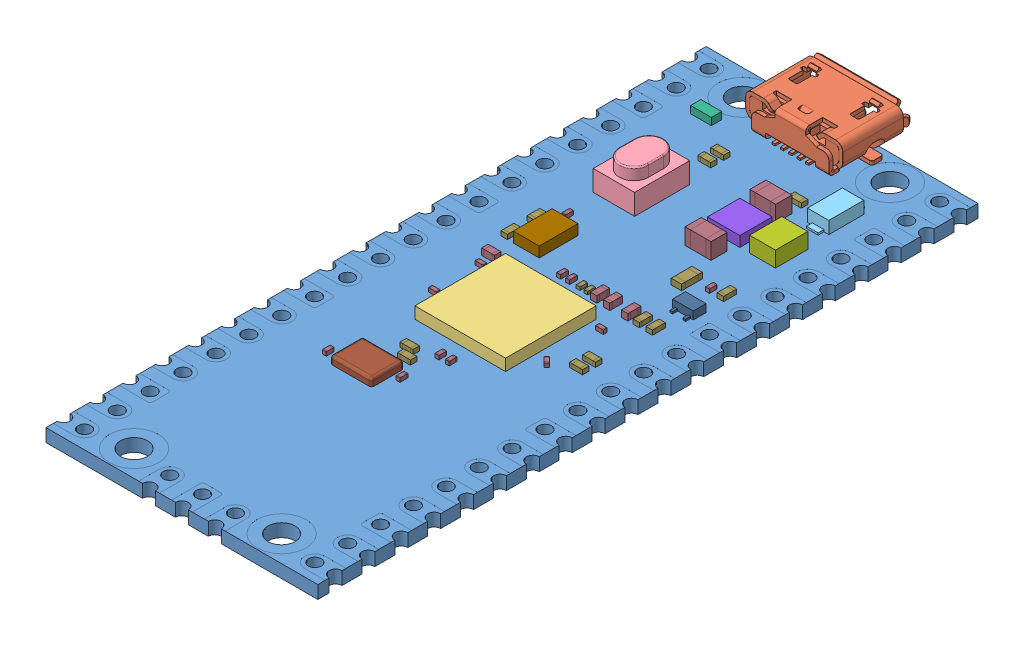
SolidWorks assembly Raspberry Pi Pico-R3, configuration Default. Lengths in mm.
Overall size (21 3.69 52.43).
44 component instances, 13 part files, 131 mates.
Components (placement in the parent):
- PCB, Raspberry Pi Pico-R3-1: PCB, Raspberry Pi Pico-R3 [Default] at origin size (21 1 51)
- MicroUSB Port, Raspberry Pi Pico-R3-1: MicroUSB Port, Raspberry Pi Pico-R3 [Default] at (0 0.5 -24.35) x (-1 0 0) z (0 0 -1) size (7.97 2.92 5.43)
- RP2040 Microcontroller, Raspberry Pi Pico-R3-1: RP2040 Microcontroller, Raspberry Pi Pico-R3 [Default] at (0 0.5 0.5) size (7 0.9 7)
- SW1, Tact Switch, Raspberry Pi Pico-R3-1: SW1, Tact Switch, Raspberry Pi Pico-R3 [Default] at (-3.5 0.5 -13.5) size (3.2 2.5 4.25)
- D1, Diode, Schottky, Raspberry Pi Pico-R3-1: D1, Diode, Schottky, Raspberry Pi Pico-R3 [Default] at (6 0.5 -19) size (1.65 0.95 3.6)
- D2, QSME-C194, LED, Raspberry Pi Pico-R3-1: D2, QSME-C194, LED, Raspberry Pi Pico-R3 [Default] at (-5.8 0.5 -20.8) size (1.6 0.55 0.8)
- L1, Inductor, Raspberry Pi Pico-R3-1: L1, Inductor, Raspberry Pi Pico-R3 [Default] at (6 0.5 -14.6) size (2 1.2 2.5)
- U2, RT6150B-33GQW, Buck Boost Converter, Raspberry Pi Pico-R3-1: U2, RT6150B-33GQW, Buck Boost Converter, Raspberry Pi Pico-R3 [Default] at (3 0.5 -14.6) size (2.5 0.8 2.5)
- U3, W25Q16JVUXIQ, Serial NOR Flash 16 Mbit, Raspberry Pi Pico-R3-1: U3, W25Q16JVUXIQ, Serial NOR Flash 16 Mbit, Raspberry Pi Pico-R3 [Default] at (-3.8 0.5 -6.4) size (2 0.8 3)
- Q1, MOSFET, DMG1012T, Raspberry Pi Pico-R3-1: Q1, MOSFET, DMG1012T, Raspberry Pi Pico-R3 [Default] at (6.5 0.5 -7.2) size (1.6 0.6 1.8)
- X1, X12M000000S096, 12 Mhz Crystal Resonator, Raspberry Pi Pico-R3-1: X1, X12M000000S096, 12 Mhz Crystal Resonator, Raspberry Pi Pico-R3 [Default] at (-2.2 0.5 9) size (3.2 0.6 2.5)
- SMD Resistor, Configurable, Raspberry Pi Pico-R3-1: SMD Resistor, Configurable, Raspberry Pi Pico-R3 [R1] at (6.2 0.5 1) x (0 0 -1) z (1 0 0) size (0.5 0.35 1)
- SMD Resistor, Configurable, Raspberry Pi Pico-R3-2: SMD Resistor, Configurable, Raspberry Pi Pico-R3 [R2] at (3.5 0.5 -18.6) x (0 0 -1) z (1 0 0) size (0.5 0.35 1)
- SMD Resistor, Configurable, Raspberry Pi Pico-R3-3: SMD Resistor, Configurable, Raspberry Pi Pico-R3 [R3] at (-2.7 0.5 -17.8) x (0 0 -1) z (1 0 0) size (0.5 0.35 1)
- SMD Resistor, Configurable, Raspberry Pi Pico-R3-4: SMD Resistor, Configurable, Raspberry Pi Pico-R3 [R4] at (-5.5 0.5 -5.4) x (-1 0 0) z (0 0 -1) size (0.5 0.35 1)
- SMD Resistor, Configurable, Raspberry Pi Pico-R3-5: SMD Resistor, Configurable, Raspberry Pi Pico-R3 [R5] at (7 0.5 -9.6) x (-1 0 0) z (0 0 -1) size (0.5 0.35 1)
- SMD Resistor, Configurable, Raspberry Pi Pico-R3-6: SMD Resistor, Configurable, Raspberry Pi Pico-R3 [R6] at (6.5 0.5 -4.6) x (-1 0 0) z (0 0 -1) size (0.5 0.35 1)
- SMD Resistor, Configurable, Raspberry Pi Pico-R3-7: SMD Resistor, Configurable, Raspberry Pi Pico-R3 [R7] at (4.5 0.5 -9) x (-1 0 0) z (0 0 -1) size (0.8 0.45 1.6)
- SMD Resistor, Configurable, Raspberry Pi Pico-R3-8: SMD Resistor, Configurable, Raspberry Pi Pico-R3 [R8] at (-2.7 0.5 -18.8) x (0 0 -1) z (1 0 0) size (0.5 0.35 1)
- SMD Resistor, Configurable, Raspberry Pi Pico-R3-9: SMD Resistor, Configurable, Raspberry Pi Pico-R3 [R9] at (5.5 0.5 -4.6) x (-1 0 0) z (0 0 -1) size (0.5 0.35 1)
- SMD Resistor, Configurable, Raspberry Pi Pico-R3-10: SMD Resistor, Configurable, Raspberry Pi Pico-R3 [R10] at (6.2 0.5 0) x (0 0 -1) z (1 0 0) size (0.5 0.35 1)
- SMD Resistor, Configurable, Raspberry Pi Pico-R3-11: SMD Resistor, Configurable, Raspberry Pi Pico-R3 [R11] at (-5.5 0.5 -7.4) size (0.5 0.35 1)
- SMD Resistor, Configurable, Raspberry Pi Pico-R3-12: SMD Resistor, Configurable, Raspberry Pi Pico-R3 [R12] at (0.8 0.5 -4.6) x (-1 0 0) z (0 0 -1) size (0.3 0.23 0.6)
- SMD Resistor, Configurable, Raspberry Pi Pico-R3-13: SMD Resistor, Configurable, Raspberry Pi Pico-R3 [R13] at (1.4 0.5 -4.6) x (-1 0 0) z (0 0 -1) size (0.3 0.23 0.6)
- SMD Resistor, Configurable, Raspberry Pi Pico-R3-14: SMD Resistor, Configurable, Raspberry Pi Pico-R3 [R14] at (-1.1 0.5 7) x (0 0 -1) z (1 0 0) size (0.5 0.35 1)
- SMD Resistor, Configurable, Raspberry Pi Pico-R3-15: SMD Resistor, Configurable, Raspberry Pi Pico-R3 [R15] at (-1.7 0.5 6.2) x (0 0 -1) z (1 0 0) size (0.5 0.35 1)
- SMD Capacitor, Configurable, Raspberry Pi Pico-R3-1: SMD Capacitor, Configurable, Raspberry Pi Pico-R3 [C1] at (3 0.5 -17) x (0 0 -1) z (1 0 0) size (1.25 1.25 2)
- SMD Capacitor, Configurable, Raspberry Pi Pico-R3-2: SMD Capacitor, Configurable, Raspberry Pi Pico-R3 [C2] at (3 0.5 -12) x (0 0 -1) z (1 0 0) size (1.25 1.25 2)
- SMD Capacitor, Configurable, Raspberry Pi Pico-R3-3: SMD Capacitor, Configurable, Raspberry Pi Pico-R3 [C3] at (6 0.5 -9.4) size (0.3 0.3 0.6)
- SMD Capacitor, Configurable, Raspberry Pi Pico-R3-4: SMD Capacitor, Configurable, Raspberry Pi Pico-R3 [C4] at (-4.5 0.5 -2.1) x (0 0 1) z (-1 0 0) size (0.3 0.3 0.6)
- SMD Capacitor, Configurable, Raspberry Pi Pico-R3-5: SMD Capacitor, Configurable, Raspberry Pi Pico-R3 [C5] at (-4.5 0.5 1.5) x (0 0 1) z (-1 0 0) size (0.3 0.3 0.6)
- SMD Capacitor, Configurable, Raspberry Pi Pico-R3-6: SMD Capacitor, Configurable, Raspberry Pi Pico-R3 [C6] at (4.6 0.5 1.9) x (0.707107 0 -0.707107) z (0.707107 0 0.707107) size (0.3 0.3 0.6)
- SMD Capacitor, Configurable, Raspberry Pi Pico-R3-7: SMD Capacitor, Configurable, Raspberry Pi Pico-R3 [C7] at (4.5 0.5 -2.4) x (0 0 1) z (-1 0 0) size (0.3 0.3 0.6)
- SMD Capacitor, Configurable, Raspberry Pi Pico-R3-8: SMD Capacitor, Configurable, Raspberry Pi Pico-R3 [C8] at (0 0.5 5.5) size (0.3 0.3 0.6)
- SMD Capacitor, Configurable, Raspberry Pi Pico-R3-9: SMD Capacitor, Configurable, Raspberry Pi Pico-R3 [C9] at (0.8 0.5 5.5) size (0.3 0.3 0.6)
- SMD Capacitor, Configurable, Raspberry Pi Pico-R3-10: SMD Capacitor, Configurable, Raspberry Pi Pico-R3 [C10] at (0 0.5 -4.6) size (0.3 0.3 0.6)
- SMD Capacitor, Configurable, Raspberry Pi Pico-R3-11: SMD Capacitor, Configurable, Raspberry Pi Pico-R3 [C11] at (-0.7 0.5 -4.6) size (0.3 0.3 0.6)
- SMD Capacitor, Configurable, Raspberry Pi Pico-R3-19: SMD Capacitor, Configurable, Raspberry Pi Pico-R3 [C12] at (2.2 0.5 -4.6) size (0.5 0.5 1)
- SMD Capacitor, Configurable, Raspberry Pi Pico-R3-20: SMD Capacitor, Configurable, Raspberry Pi Pico-R3 [C13] at (4.6 0.5 -4.6) size (0.5 0.5 1)
- SMD Capacitor, Configurable, Raspberry Pi Pico-R3-21: SMD Capacitor, Configurable, Raspberry Pi Pico-R3 [C14] at (3.2 0.5 -4.6) size (0.5 0.5 1)
- SMD Capacitor, Configurable, Raspberry Pi Pico-R3-22: SMD Capacitor, Configurable, Raspberry Pi Pico-R3 [C15] at (-4.5 0.5 -8.8) size (0.3 0.3 0.6)
- SMD Capacitor, Configurable, Raspberry Pi Pico-R3-23: SMD Capacitor, Configurable, Raspberry Pi Pico-R3 [C16] at (-4.6 0.5 9.6) size (0.3 0.3 0.6)
- SMD Capacitor, Configurable, Raspberry Pi Pico-R3-24: SMD Capacitor, Configurable, Raspberry Pi Pico-R3 [C17] at (0 0.5 8.5) size (0.3 0.3 0.6)
- SMD Capacitor, Configurable, Raspberry Pi Pico-R3-18: SMD Capacitor, Configurable, Raspberry Pi Pico-R3 [C18] at (-4.7 0.5 -3.1) x (0 0 1) z (-1 0 0) size (0.5 0.5 1)
Mates (geometry in assembly coordinates):
- Coincident1: coordinate: point of assembly; point of PCB, Raspberry Pi Pico-R3-1; point of assembly
- Coincident2: coincident: plane of assembly through (0 0 0) normal (1 0 0); plane of MicroUSB Port, Raspberry Pi Pico-R3-1 through (0 0.5 -24.35) normal (-1 0 0); plane of assembly
- Coincident4: coincident: plane of assembly; plane of assembly; plane of PCB, Raspberry Pi Pico-R3-1 through (0 0.5 0) normal (0 1 0); plane of MicroUSB Port, Raspberry Pi Pico-R3-1 through (0 0.5 -24.35) normal (0 1 0)
- Distance1: distance: plane of assembly; plane of assembly; plane of PCB, Raspberry Pi Pico-R3-1 through (-10.5 -0.5 -25.5) normal (0 0 -1); plane of MicroUSB Port, Raspberry Pi Pico-R3-1 through (-1.2 2.0268 -21.5) normal (0 0 1)
- Coincident5: coincident: plane of assembly; plane of assembly; plane of PCB, Raspberry Pi Pico-R3-1 through (0 0.5 0) normal (0 1 0); plane of RP2040 Microcontroller, Raspberry Pi Pico-R3-1 through (0 0.5 0.5) normal (0 -1 0)
- Coincident6: coincident: plane of assembly through (0 0 0) normal (1 0 0); plane of RP2040 Microcontroller, Raspberry Pi Pico-R3-1 through (0 0.5 0.5) normal (1 0 0); plane of assembly
- Coincident7: coincident: plane of assembly; plane of assembly; plane of PCB, Raspberry Pi Pico-R3-1 through (0 0.5 0) normal (0 1 0); plane of SW1, Tact Switch, Raspberry Pi Pico-R3-1 through (-3.5 0.5 -13.5) normal (0 -1 0)
- Distance2: distance = 3.5 mm: plane of assembly through (0 0 0) normal (1 0 0); plane of SW1, Tact Switch, Raspberry Pi Pico-R3-1 through (-3.5 0.5 -13.5) normal (1 0 0); plane of assembly
- Distance3: distance = 13.5 mm: plane of assembly through (0 0 0) normal (0 0 1); plane of assembly; plane of SW1, Tact Switch, Raspberry Pi Pico-R3-1 through (-3.5 0.5 -13.5) normal (0 0 1)
- Coincident8: coincident: plane of assembly; plane of assembly; plane of PCB, Raspberry Pi Pico-R3-1 through (0 0.5 0) normal (0 1 0); plane of D1, Diode, Schottky, Raspberry Pi Pico-R3-1 through (6 0.5 -19) normal (0 -1 0)
- Distance4: distance = 6 mm: plane of assembly through (0 0 0) normal (1 0 0); plane of D1, Diode, Schottky, Raspberry Pi Pico-R3-1 through (6 0.5 -19) normal (1 0 0); plane of assembly
- Distance5: distance = 19 mm: plane of assembly through (0 0 0) normal (0 0 1); plane of assembly; plane of D1, Diode, Schottky, Raspberry Pi Pico-R3-1 through (6 0.5 -19) normal (0 0 1)
- Coincident9: coincident: plane of assembly; plane of assembly; plane of PCB, Raspberry Pi Pico-R3-1 through (0 0.5 0) normal (0 1 0); plane of L1, Inductor, Raspberry Pi Pico-R3-1 through (6 0.5 -14.6) normal (0 -1 0)
- Coincident10: coincident: plane of assembly; plane of assembly; plane of D1, Diode, Schottky, Raspberry Pi Pico-R3-1 through (6 0.5 -19) normal (1 0 0); plane of L1, Inductor, Raspberry Pi Pico-R3-1 through (6 0.5 -14.6) normal (1 0 0)
- Distance6: distance = 4.4 mm: plane of assembly; plane of assembly; plane of L1, Inductor, Raspberry Pi Pico-R3-1 through (6 0.5 -14.6) normal (0 0 1); plane of D1, Diode, Schottky, Raspberry Pi Pico-R3-1 through (6 0.5 -19) normal (0 0 1)
- Coincident11: coincident: plane of assembly; plane of assembly; plane of PCB, Raspberry Pi Pico-R3-1 through (0 0.5 0) normal (0 1 0); plane of SMD Resistor, Configurable, Raspberry Pi Pico-R3-1 through (6.2 0.5 1) normal (0 -1 0)
- Distance8: distance = 6.2 mm: plane of assembly through (0 0 0) normal (1 0 0); plane of SMD Resistor, Configurable, Raspberry Pi Pico-R3-1 through (6.2 0.5 1) normal (1 0 0); plane of assembly
- Distance9: distance = 1 mm: plane of assembly through (0 0 0) normal (0 0 1); plane of SMD Resistor, Configurable, Raspberry Pi Pico-R3-1 through (6.2 0.5 1) normal (0 0 -1); plane of assembly
- Coincident13: coincident: plane of assembly; plane of assembly; plane of PCB, Raspberry Pi Pico-R3-1 through (0 0.5 0) normal (0 1 0); plane of SMD Resistor, Configurable, Raspberry Pi Pico-R3-2 through (3.5 0.5 -18.6) normal (0 -1 0)
- Distance10: distance = 3.5 mm: plane of assembly through (0 0 0) normal (1 0 0); plane of SMD Resistor, Configurable, Raspberry Pi Pico-R3-2 through (3.5 0.5 -18.6) normal (1 0 0); plane of assembly
- Distance11: distance = 18.6 mm: plane of assembly through (0 0 0) normal (0 0 1); plane of SMD Resistor, Configurable, Raspberry Pi Pico-R3-2 through (3.5 0.5 -18.6) normal (0 0 -1); plane of assembly
- Coincident14: coincident: plane of assembly; plane of assembly; plane of PCB, Raspberry Pi Pico-R3-1 through (0 0.5 0) normal (0 1 0); plane of SMD Resistor, Configurable, Raspberry Pi Pico-R3-3 through (-2.7 0.5 -17.8) normal (0 -1 0)
- Coincident15: coincident: plane of assembly; plane of assembly; plane of PCB, Raspberry Pi Pico-R3-1 through (0 0.5 0) normal (0 1 0); plane of SMD Resistor, Configurable, Raspberry Pi Pico-R3-4 through (-5.5 0.5 -5.4) normal (0 -1 0)
- Coincident16: coincident: plane of assembly; plane of assembly; plane of PCB, Raspberry Pi Pico-R3-1 through (0 0.5 0) normal (0 1 0); plane of SMD Resistor, Configurable, Raspberry Pi Pico-R3-5 through (7 0.5 -9.6) normal (0 -1 0)
- Coincident17: coincident: plane of assembly; plane of assembly; plane of PCB, Raspberry Pi Pico-R3-1 through (0 0.5 0) normal (0 1 0); plane of SMD Resistor, Configurable, Raspberry Pi Pico-R3-6 through (6.5 0.5 -4.6) normal (0 -1 0)
- Coincident18: coincident: plane of assembly; plane of assembly; plane of PCB, Raspberry Pi Pico-R3-1 through (0 0.5 0) normal (0 1 0); plane of SMD Resistor, Configurable, Raspberry Pi Pico-R3-7 through (4.5 0.5 -9) normal (0 -1 0)
- Coincident19: coincident: plane of assembly; plane of assembly; plane of PCB, Raspberry Pi Pico-R3-1 through (0 0.5 0) normal (0 1 0); plane of SMD Resistor, Configurable, Raspberry Pi Pico-R3-8 through (-2.7 0.5 -18.8) normal (0 -1 0)
- Coincident20: coincident: plane of assembly; plane of assembly; plane of PCB, Raspberry Pi Pico-R3-1 through (0 0.5 0) normal (0 1 0); plane of SMD Resistor, Configurable, Raspberry Pi Pico-R3-9 through (5.5 0.5 -4.6) normal (0 -1 0)
- Coincident21: coincident: plane of assembly; plane of assembly; plane of PCB, Raspberry Pi Pico-R3-1 through (0 0.5 0) normal (0 1 0); plane of SMD Resistor, Configurable, Raspberry Pi Pico-R3-10 through (6.2 0.5 0) normal (0 -1 0)
- Coincident22: coincident: plane of assembly; plane of assembly; plane of PCB, Raspberry Pi Pico-R3-1 through (0 0.5 0) normal (0 1 0); plane of SMD Resistor, Configurable, Raspberry Pi Pico-R3-11 through (-5.5 0.5 -7.4) normal (0 -1 0)
- Coincident23: coincident: plane of assembly; plane of assembly; plane of PCB, Raspberry Pi Pico-R3-1 through (0 0.5 0) normal (0 1 0); plane of SMD Resistor, Configurable, Raspberry Pi Pico-R3-12 through (0.8 0.5 -4.6) normal (0 -1 0)
- Coincident24: coincident: plane of assembly; plane of assembly; plane of PCB, Raspberry Pi Pico-R3-1 through (0 0.5 0) normal (0 1 0); plane of SMD Resistor, Configurable, Raspberry Pi Pico-R3-13 through (1.4 0.5 -4.6) normal (0 -1 0)
- Coincident25: coincident: plane of assembly; plane of assembly; plane of PCB, Raspberry Pi Pico-R3-1 through (0 0.5 0) normal (0 1 0); plane of SMD Resistor, Configurable, Raspberry Pi Pico-R3-14 through (-1.1 0.5 7) normal (0 -1 0)
- Coincident26: coincident: plane of assembly; plane of assembly; plane of PCB, Raspberry Pi Pico-R3-1 through (0 0.5 0) normal (0 1 0); plane of SMD Resistor, Configurable, Raspberry Pi Pico-R3-15 through (-1.7 0.5 6.2) normal (0 -1 0)
- Distance12: distance = 2.7 mm: plane of assembly through (0 0 0) normal (1 0 0); plane of SMD Resistor, Configurable, Raspberry Pi Pico-R3-3 through (-2.7 0.5 -17.8) normal (1 0 0); plane of assembly
- Coincident27: coincident: plane of assembly; plane of assembly; plane of SMD Resistor, Configurable, Raspberry Pi Pico-R3-3 through (-2.7 0.5 -17.8) normal (1 0 0); plane of SMD Resistor, Configurable, Raspberry Pi Pico-R3-8 through (-2.7 0.5 -18.8) normal (1 0 0)
- Distance14: distance = 1 mm: plane of assembly; plane of assembly; plane of SMD Resistor, Configurable, Raspberry Pi Pico-R3-3 through (-2.7 0.5 -17.8) normal (0 0 -1); plane of SMD Resistor, Configurable, Raspberry Pi Pico-R3-8 through (-2.7 0.5 -18.8) normal (0 0 -1)
- Distance15: distance = 17.8 mm: plane of assembly through (0 0 0) normal (0 0 1); plane of SMD Resistor, Configurable, Raspberry Pi Pico-R3-3 through (-2.7 0.5 -17.8) normal (0 0 -1); plane of assembly
- Coincident28: coincident: plane of assembly; plane of assembly; plane of SMD Resistor, Configurable, Raspberry Pi Pico-R3-4 through (-5.5 0.5 -5.4) normal (-1 0 0); plane of SMD Resistor, Configurable, Raspberry Pi Pico-R3-11 through (-5.5 0.5 -7.4) normal (1 0 0)
- Distance16: distance = 5.5 mm: plane of assembly through (0 0 0) normal (1 0 0); plane of assembly; plane of SMD Resistor, Configurable, Raspberry Pi Pico-R3-4 through (-5.5 0.5 -5.4) normal (-1 0 0)
- Distance17: distance = 5.4 mm: plane of assembly through (0 0 0) normal (0 0 1); plane of SMD Resistor, Configurable, Raspberry Pi Pico-R3-4 through (-5.5 0.5 -5.4) normal (0 0 -1); plane of assembly
- Distance18: distance = 2 mm: plane of assembly; plane of assembly; plane of SMD Resistor, Configurable, Raspberry Pi Pico-R3-4 through (-5.5 0.5 -5.4) normal (0 0 -1); plane of SMD Resistor, Configurable, Raspberry Pi Pico-R3-11 through (-5.5 0.5 -7.4) normal (0 0 1)
- Distance19: distance = 4.5 mm: plane of assembly through (0 0 0) normal (1 0 0); plane of SMD Resistor, Configurable, Raspberry Pi Pico-R3-7 through (4.5 0.5 -9) normal (-1 0 0); plane of assembly
- Distance20: distance = 9 mm: plane of assembly through (0 0 0) normal (0 0 1); plane of SMD Resistor, Configurable, Raspberry Pi Pico-R3-7 through (4.5 0.5 -9) normal (0 0 -1); plane of assembly
- Distance21: distance = 7 mm: plane of assembly through (0 0 0) normal (1 0 0); plane of SMD Resistor, Configurable, Raspberry Pi Pico-R3-5 through (7 0.5 -9.6) normal (-1 0 0); plane of assembly
- Distance22: distance = 9.6 mm: plane of assembly through (0 0 0) normal (0 0 1); plane of SMD Resistor, Configurable, Raspberry Pi Pico-R3-5 through (7 0.5 -9.6) normal (0 0 -1); plane of assembly
- Coincident29: coincident: plane of assembly; plane of assembly; plane of SMD Resistor, Configurable, Raspberry Pi Pico-R3-6 through (6.5 0.5 -4.6) normal (0 0 -1); plane of SMD Resistor, Configurable, Raspberry Pi Pico-R3-9 through (5.5 0.5 -4.6) normal (0 0 -1)
- Distance23: distance = 6.5 mm: plane of assembly through (0 0 0) normal (1 0 0); plane of SMD Resistor, Configurable, Raspberry Pi Pico-R3-6 through (6.5 0.5 -4.6) normal (-1 0 0); plane of assembly
- Distance24: distance = 1 mm: plane of assembly; plane of assembly; plane of SMD Resistor, Configurable, Raspberry Pi Pico-R3-9 through (5.5 0.5 -4.6) normal (-1 0 0); plane of SMD Resistor, Configurable, Raspberry Pi Pico-R3-6 through (6.5 0.5 -4.6) normal (-1 0 0)
- Coincident30: coincident: plane of assembly; plane of assembly; plane of SMD Resistor, Configurable, Raspberry Pi Pico-R3-1 through (6.2 0.5 1) normal (1 0 0); plane of SMD Resistor, Configurable, Raspberry Pi Pico-R3-10 through (6.2 0.5 0) normal (1 0 0)
- Distance25: distance = 1 mm: plane of assembly; plane of assembly; plane of SMD Resistor, Configurable, Raspberry Pi Pico-R3-1 through (6.2 0.5 1) normal (0 0 -1); plane of SMD Resistor, Configurable, Raspberry Pi Pico-R3-10 through (6.2 0.5 0) normal (0 0 -1)
- Distance26: distance = 0.8 mm: plane of assembly through (0 0 0) normal (1 0 0); plane of SMD Resistor, Configurable, Raspberry Pi Pico-R3-12 through (0.8 0.5 -4.6) normal (-1 0 0); plane of assembly
- Distance27: distance = 0.6 mm: plane of assembly; plane of assembly; plane of SMD Resistor, Configurable, Raspberry Pi Pico-R3-13 through (1.4 0.5 -4.6) normal (-1 0 0); plane of SMD Resistor, Configurable, Raspberry Pi Pico-R3-12 through (0.8 0.5 -4.6) normal (-1 0 0)
- Coincident31: coincident: plane of assembly; plane of assembly; plane of SMD Resistor, Configurable, Raspberry Pi Pico-R3-12 through (0.8 0.5 -4.6) normal (0 0 -1); plane of SMD Resistor, Configurable, Raspberry Pi Pico-R3-13 through (1.4 0.5 -4.6) normal (0 0 -1)
- Distance28: distance = 4.6 mm: plane of assembly through (0 0 0) normal (0 0 1); plane of SMD Resistor, Configurable, Raspberry Pi Pico-R3-12 through (0.8 0.5 -4.6) normal (0 0 -1); plane of assembly
- Distance29: distance = 0.6 mm: plane of assembly; plane of assembly; plane of SMD Resistor, Configurable, Raspberry Pi Pico-R3-14 through (-1.1 0.5 7) normal (1 0 0); plane of SMD Resistor, Configurable, Raspberry Pi Pico-R3-15 through (-1.7 0.5 6.2) normal (1 0 0)
- Distance30: distance = 0.8 mm: plane of assembly; plane of assembly; plane of SMD Resistor, Configurable, Raspberry Pi Pico-R3-14 through (-1.1 0.5 7) normal (0 0 -1); plane of SMD Resistor, Configurable, Raspberry Pi Pico-R3-15 through (-1.7 0.5 6.2) normal (0 0 -1)
- Distance31: distance = 7 mm: plane of assembly through (0 0 0) normal (0 0 1); plane of SMD Resistor, Configurable, Raspberry Pi Pico-R3-14 through (-1.1 0.5 7) normal (0 0 -1); plane of assembly
- Distance32: distance = 4.6 mm: plane of assembly through (0 0 0) normal (0 0 1); plane of SMD Resistor, Configurable, Raspberry Pi Pico-R3-9 through (5.5 0.5 -4.6) normal (0 0 -1); plane of assembly
- Distance33: distance = 0.5 mm: plane of assembly through (0 0 0) normal (0 0 1); plane of RP2040 Microcontroller, Raspberry Pi Pico-R3-1 through (0 0.5 0.5) normal (0 0 1); plane of assembly
- Distance34: distance = 1.1 mm: plane of assembly through (0 0 0) normal (1 0 0); plane of SMD Resistor, Configurable, Raspberry Pi Pico-R3-14 through (-1.1 0.5 7) normal (1 0 0); plane of assembly
- Coincident32: coincident: plane of assembly; plane of assembly; plane of PCB, Raspberry Pi Pico-R3-1 through (0 0.5 0) normal (0 1 0); plane of SMD Capacitor, Configurable, Raspberry Pi Pico-R3-1 through (3 0.5 -17) normal (0 -1 0)
- Coincident33: coincident: plane of assembly; plane of assembly; plane of PCB, Raspberry Pi Pico-R3-1 through (0 0.5 0) normal (0 1 0); plane of SMD Capacitor, Configurable, Raspberry Pi Pico-R3-2 through (3 0.5 -12) normal (0 -1 0)
- Coincident34: coincident: plane of assembly; plane of assembly; plane of PCB, Raspberry Pi Pico-R3-1 through (0 0.5 0) normal (0 1 0); plane of SMD Capacitor, Configurable, Raspberry Pi Pico-R3-3 through (6 0.5 -9.4) normal (0 -1 0)
- Coincident35: coincident: plane of assembly; plane of assembly; plane of PCB, Raspberry Pi Pico-R3-1 through (0 0.5 0) normal (0 1 0); plane of SMD Capacitor, Configurable, Raspberry Pi Pico-R3-18 through (-4.7 0.5 -3.1) normal (0 -1 0)
- Coincident36: coincident: plane of assembly; plane of assembly; plane of PCB, Raspberry Pi Pico-R3-1 through (0 0.5 0) normal (0 1 0); plane of SMD Capacitor, Configurable, Raspberry Pi Pico-R3-10 through (0 0.5 -4.6) normal (0 -1 0)
- Coincident37: coincident: plane of assembly; plane of assembly; plane of PCB, Raspberry Pi Pico-R3-1 through (0 0.5 0) normal (0 1 0); plane of SMD Capacitor, Configurable, Raspberry Pi Pico-R3-9 through (0.8 0.5 5.5) normal (0 -1 0)
- Coincident38: coincident: plane of assembly; plane of assembly; plane of PCB, Raspberry Pi Pico-R3-1 through (0 0.5 0) normal (0 1 0); plane of SMD Capacitor, Configurable, Raspberry Pi Pico-R3-8 through (0 0.5 5.5) normal (0 -1 0)
- Coincident39: coincident: plane of assembly; plane of assembly; plane of PCB, Raspberry Pi Pico-R3-1 through (0 0.5 0) normal (0 1 0); plane of SMD Capacitor, Configurable, Raspberry Pi Pico-R3-7 through (4.5 0.5 -2.4) normal (0 -1 0)
- Coincident40: coincident: plane of assembly; plane of assembly; plane of PCB, Raspberry Pi Pico-R3-1 through (0 0.5 0) normal (0 1 0); plane of SMD Capacitor, Configurable, Raspberry Pi Pico-R3-6 through (4.6 0.5 1.9) normal (0 -1 0)
- Coincident41: coincident: plane of assembly; plane of assembly; plane of PCB, Raspberry Pi Pico-R3-1 through (0 0.5 0) normal (0 1 0); plane of SMD Capacitor, Configurable, Raspberry Pi Pico-R3-5 through (-4.5 0.5 1.5) normal (0 -1 0)
- Coincident42: coincident: plane of assembly; plane of assembly; plane of PCB, Raspberry Pi Pico-R3-1 through (0 0.5 0) normal (0 1 0); plane of SMD Capacitor, Configurable, Raspberry Pi Pico-R3-4 through (-4.5 0.5 -2.1) normal (0 -1 0)
- Coincident43: coincident: plane of assembly; plane of assembly; plane of PCB, Raspberry Pi Pico-R3-1 through (0 0.5 0) normal (0 1 0); plane of SMD Capacitor, Configurable, Raspberry Pi Pico-R3-11 through (-0.7 0.5 -4.6) normal (0 -1 0)
- Coincident44: coincident: plane of assembly; plane of assembly; plane of PCB, Raspberry Pi Pico-R3-1 through (0 0.5 0) normal (0 1 0); plane of SMD Capacitor, Configurable, Raspberry Pi Pico-R3-19 through (2.2 0.5 -4.6) normal (0 -1 0)
- Coincident45: coincident: plane of assembly; plane of assembly; plane of PCB, Raspberry Pi Pico-R3-1 through (0 0.5 0) normal (0 1 0); plane of SMD Capacitor, Configurable, Raspberry Pi Pico-R3-20 through (4.6 0.5 -4.6) normal (0 -1 0)
- Coincident46: coincident: plane of assembly; plane of assembly; plane of PCB, Raspberry Pi Pico-R3-1 through (0 0.5 0) normal (0 1 0); plane of SMD Capacitor, Configurable, Raspberry Pi Pico-R3-21 through (3.2 0.5 -4.6) normal (0 -1 0)
- Coincident47: coincident: plane of assembly; plane of assembly; plane of PCB, Raspberry Pi Pico-R3-1 through (0 0.5 0) normal (0 1 0); plane of SMD Capacitor, Configurable, Raspberry Pi Pico-R3-22 through (-4.5 0.5 -8.8) normal (0 -1 0)
- Coincident48: coincident: plane of assembly; plane of assembly; plane of PCB, Raspberry Pi Pico-R3-1 through (0 0.5 0) normal (0 1 0); plane of SMD Capacitor, Configurable, Raspberry Pi Pico-R3-23 through (-4.6 0.5 9.6) normal (0 -1 0)
- Coincident49: coincident: plane of assembly; plane of assembly; plane of PCB, Raspberry Pi Pico-R3-1 through (0 0.5 0) normal (0 1 0); plane of SMD Capacitor, Configurable, Raspberry Pi Pico-R3-24 through (0 0.5 8.5) normal (0 -1 0)
- Coincident50: coincident: plane of assembly; plane of assembly; plane of SMD Capacitor, Configurable, Raspberry Pi Pico-R3-1 through (3 0.5 -17) normal (1 0 0); plane of SMD Capacitor, Configurable, Raspberry Pi Pico-R3-2 through (3 0.5 -12) normal (1 0 0)
- Distance35: distance = 3 mm: plane of assembly through (0 0 0) normal (1 0 0); plane of SMD Capacitor, Configurable, Raspberry Pi Pico-R3-1 through (3 0.5 -17) normal (1 0 0); plane of assembly
- Distance36: distance = 17 mm: plane of assembly through (0 0 0) normal (0 0 1); plane of SMD Capacitor, Configurable, Raspberry Pi Pico-R3-1 through (3 0.5 -17) normal (0 0 -1); plane of assembly
- Distance37: distance = 12 mm: plane of assembly through (0 0 0) normal (0 0 1); plane of SMD Capacitor, Configurable, Raspberry Pi Pico-R3-2 through (3 0.5 -12) normal (0 0 -1); plane of assembly
- Distance38: distance = 4.5 mm: plane of assembly through (0 0 0) normal (1 0 0); plane of SMD Capacitor, Configurable, Raspberry Pi Pico-R3-22 through (-4.5 0.5 -8.8) normal (1 0 0); plane of assembly
- Distance39: distance = 8.8 mm: plane of assembly through (0 0 0) normal (0 0 1); plane of SMD Capacitor, Configurable, Raspberry Pi Pico-R3-22 through (-4.5 0.5 -8.8) normal (0 0 1); plane of assembly
- Distance40: distance = 4.6 mm: plane of assembly through (0 0 0) normal (1 0 0); plane of SMD Capacitor, Configurable, Raspberry Pi Pico-R3-23 through (-4.6 0.5 9.6) normal (1 0 0); plane of assembly
- Distance41: distance = 9.6 mm: plane of assembly through (0 0 0) normal (0 0 1); plane of SMD Capacitor, Configurable, Raspberry Pi Pico-R3-23 through (-4.6 0.5 9.6) normal (0 0 1); plane of assembly
- Distance42: distance = 0 mm: plane of assembly through (0 0 0) normal (1 0 0); plane of SMD Capacitor, Configurable, Raspberry Pi Pico-R3-24 through (0 0.5 8.5) normal (1 0 0); plane of assembly
- Distance43: distance = 8.5 mm: plane of assembly through (0 0 0) normal (0 0 1); plane of SMD Capacitor, Configurable, Raspberry Pi Pico-R3-24 through (0 0.5 8.5) normal (0 0 1); plane of assembly
- Distance44: distance = 1.5 mm: plane of assembly through (0 0 0) normal (0 0 1); plane of SMD Capacitor, Configurable, Raspberry Pi Pico-R3-5 through (-4.5 0.5 1.5) normal (0 0 1); plane of assembly
- Distance45: distance = 4.5 mm: plane of assembly through (0 0 0) normal (1 0 0); plane of SMD Capacitor, Configurable, Raspberry Pi Pico-R3-5 through (-4.5 0.5 1.5) normal (-1 0 0); plane of assembly
- Coincident54: coincident: plane of assembly; plane of assembly; plane of SMD Capacitor, Configurable, Raspberry Pi Pico-R3-4 through (-4.5 0.5 -2.1) normal (-1 0 0); plane of SMD Capacitor, Configurable, Raspberry Pi Pico-R3-5 through (-4.5 0.5 1.5) normal (-1 0 0)
- Distance46: distance = 3.6 mm: plane of assembly; plane of assembly; plane of SMD Capacitor, Configurable, Raspberry Pi Pico-R3-4 through (-4.5 0.5 -2.1) normal (0 0 1); plane of SMD Capacitor, Configurable, Raspberry Pi Pico-R3-5 through (-4.5 0.5 1.5) normal (0 0 1)
- Coincident55: coincident: plane of assembly; plane of assembly; plane of SMD Capacitor, Configurable, Raspberry Pi Pico-R3-8 through (0 0.5 5.5) normal (0 0 1); plane of SMD Capacitor, Configurable, Raspberry Pi Pico-R3-9 through (0.8 0.5 5.5) normal (0 0 1)
- Coincident56: coincident: plane of assembly through (0 0 0) normal (1 0 0); plane of SMD Capacitor, Configurable, Raspberry Pi Pico-R3-8 through (0 0.5 5.5) normal (1 0 0); plane of assembly
- Distance47: distance = 0.8 mm: plane of assembly; plane of assembly; plane of SMD Capacitor, Configurable, Raspberry Pi Pico-R3-9 through (0.8 0.5 5.5) normal (1 0 0); plane of SMD Capacitor, Configurable, Raspberry Pi Pico-R3-8 through (0 0.5 5.5) normal (1 0 0)
- Distance48: distance = 5.5 mm: plane of assembly through (0 0 0) normal (0 0 1); plane of SMD Capacitor, Configurable, Raspberry Pi Pico-R3-8 through (0 0.5 5.5) normal (0 0 1); plane of assembly
- Distance49: distance = 4.7 mm: plane of assembly through (0 0 0) normal (1 0 0); plane of SMD Capacitor, Configurable, Raspberry Pi Pico-R3-18 through (-4.7 0.5 -3.1) normal (-1 0 0); plane of assembly
- Distance50: distance = 1 mm: plane of assembly; plane of assembly; plane of SMD Capacitor, Configurable, Raspberry Pi Pico-R3-18 through (-4.7 0.5 -3.1) normal (0 0 1); plane of SMD Capacitor, Configurable, Raspberry Pi Pico-R3-4 through (-4.5 0.5 -2.1) normal (0 0 1)
- Distance51: distance = 4.5 mm: plane of assembly through (0 0 0) normal (1 0 0); plane of SMD Capacitor, Configurable, Raspberry Pi Pico-R3-7 through (4.5 0.5 -2.4) normal (-1 0 0); plane of assembly
- Distance52: distance = 2.4 mm: plane of assembly through (0 0 0) normal (0 0 1); plane of SMD Capacitor, Configurable, Raspberry Pi Pico-R3-7 through (4.5 0.5 -2.4) normal (0 0 1); plane of assembly
- Angle1: planar angle = 0.785398 rad: plane of assembly through (0 0 0) normal (1 0 0); plane of SMD Capacitor, Configurable, Raspberry Pi Pico-R3-6 through (4.6 0.5 1.9) normal (0.707107 0 -0.707107); plane of assembly
- Distance53: distance = 4.6 mm: point of assembly; point of SMD Capacitor, Configurable, Raspberry Pi Pico-R3-6; plane of assembly
- Distance54: distance = 1.9 mm: point of assembly; point of SMD Capacitor, Configurable, Raspberry Pi Pico-R3-6; plane of assembly
- Coincident61: coincident: plane of assembly; plane of assembly; plane of SMD Resistor, Configurable, Raspberry Pi Pico-R3-9 through (5.5 0.5 -4.6) normal (0 0 -1); plane of SMD Capacitor, Configurable, Raspberry Pi Pico-R3-20 through (4.6 0.5 -4.6) normal (0 0 1)
- Coincident62: coincident: plane of assembly; plane of assembly; plane of SMD Capacitor, Configurable, Raspberry Pi Pico-R3-20 through (4.6 0.5 -4.6) normal (0 0 1); plane of SMD Capacitor, Configurable, Raspberry Pi Pico-R3-10 through (0 0.5 -4.6) normal (0 0 1)
- Coincident63: coincident: plane of assembly; plane of assembly; plane of SMD Capacitor, Configurable, Raspberry Pi Pico-R3-20 through (4.6 0.5 -4.6) normal (0 0 1); plane of SMD Capacitor, Configurable, Raspberry Pi Pico-R3-11 through (-0.7 0.5 -4.6) normal (0 0 1)
- Coincident64: coincident: plane of assembly; plane of assembly; plane of SMD Capacitor, Configurable, Raspberry Pi Pico-R3-20 through (4.6 0.5 -4.6) normal (0 0 1); plane of SMD Capacitor, Configurable, Raspberry Pi Pico-R3-19 through (2.2 0.5 -4.6) normal (0 0 1)
- Coincident65: coincident: plane of assembly; plane of assembly; plane of SMD Capacitor, Configurable, Raspberry Pi Pico-R3-20 through (4.6 0.5 -4.6) normal (0 0 1); plane of SMD Capacitor, Configurable, Raspberry Pi Pico-R3-21 through (3.2 0.5 -4.6) normal (0 0 1)
- Distance55: distance = 4.6 mm: plane of assembly through (0 0 0) normal (1 0 0); plane of SMD Capacitor, Configurable, Raspberry Pi Pico-R3-20 through (4.6 0.5 -4.6) normal (1 0 0); plane of assembly
- Distance56: distance = 3.2 mm: plane of assembly through (0 0 0) normal (1 0 0); plane of SMD Capacitor, Configurable, Raspberry Pi Pico-R3-21 through (3.2 0.5 -4.6) normal (1 0 0); plane of assembly
- Distance57: distance = 2.2 mm: plane of assembly through (0 0 0) normal (1 0 0); plane of SMD Capacitor, Configurable, Raspberry Pi Pico-R3-19 through (2.2 0.5 -4.6) normal (1 0 0); plane of assembly
- Coincident66: coincident: plane of assembly through (0 0 0) normal (1 0 0); plane of SMD Capacitor, Configurable, Raspberry Pi Pico-R3-10 through (0 0.5 -4.6) normal (1 0 0); plane of assembly
- Distance58: distance = 0.7 mm: plane of assembly through (0 0 0) normal (1 0 0); plane of SMD Capacitor, Configurable, Raspberry Pi Pico-R3-11 through (-0.7 0.5 -4.6) normal (1 0 0); plane of assembly
- Distance59: distance = 6 mm: plane of assembly through (0 0 0) normal (1 0 0); plane of SMD Capacitor, Configurable, Raspberry Pi Pico-R3-3 through (6 0.5 -9.4) normal (1 0 0); plane of assembly
- Distance60: distance = 9.4 mm: plane of assembly through (0 0 0) normal (0 0 1); plane of SMD Capacitor, Configurable, Raspberry Pi Pico-R3-3 through (6 0.5 -9.4) normal (0 0 1); plane of assembly
- Coincident67: coincident: plane of assembly; plane of assembly; plane of PCB, Raspberry Pi Pico-R3-1 through (0 0.5 0) normal (0 1 0); plane of U2, RT6150B-33GQW, Buck Boost Converter, Raspberry Pi Pico-R3-1 through (3 0.5 -14.6) normal (0 -1 0)
- Coincident68: coincident: plane of SMD Capacitor, Configurable, Raspberry Pi Pico-R3-1 through (3 0.5 -17) normal (1 0 0); plane of U2, RT6150B-33GQW, Buck Boost Converter, Raspberry Pi Pico-R3-1 through (3 0.5 -14.6) normal (1 0 0)
- Distance61: distance = 14.6 mm: plane of U2, RT6150B-33GQW, Buck Boost Converter, Raspberry Pi Pico-R3-1 through (3 0.5 -14.6) normal (0 0 1); plane of assembly through (0 0 0) normal (0 0 1)
- Coincident69: coincident: plane of assembly; plane of assembly; plane of PCB, Raspberry Pi Pico-R3-1 through (0 0.5 0) normal (0 1 0); plane of U3, W25Q16JVUXIQ, Serial NOR Flash 16 Mbit, Raspberry Pi Pico-R3-1 through (-3.8 0.5 -6.4) normal (0 -1 0)
- Distance62: distance = 3.8 mm: plane of U3, W25Q16JVUXIQ, Serial NOR Flash 16 Mbit, Raspberry Pi Pico-R3-1 through (-3.8 0.5 -6.4) normal (1 0 0); plane of assembly through (0 0 0) normal (1 0 0)
- Distance63: distance = 6.4 mm: plane of U3, W25Q16JVUXIQ, Serial NOR Flash 16 Mbit, Raspberry Pi Pico-R3-1 through (-3.8 0.5 -6.4) normal (0 0 1); plane of assembly through (0 0 0) normal (0 0 1)
- Coincident70: coincident: plane of assembly; plane of assembly; plane of PCB, Raspberry Pi Pico-R3-1 through (0 0.5 0) normal (0 1 0); plane of D2, QSME-C194, LED, Raspberry Pi Pico-R3-1 through (-5.8 0.5 -20.8) normal (0 -1 0)
- Distance64: distance = 5.8 mm: plane of D2, QSME-C194, LED, Raspberry Pi Pico-R3-1 through (-5.8 0.5 -20.8) normal (1 0 0); plane of assembly through (0 0 0) normal (1 0 0)
- Distance65: distance = 20.8 mm: plane of D2, QSME-C194, LED, Raspberry Pi Pico-R3-1 through (-5.8 0.5 -20.8) normal (0 0 1); plane of assembly through (0 0 0) normal (0 0 1)
- Coincident71: coincident: plane of assembly; plane of assembly; plane of PCB, Raspberry Pi Pico-R3-1 through (0 0.5 0) normal (0 1 0); plane of Q1, MOSFET, DMG1012T, Raspberry Pi Pico-R3-1 through (6.5 0.5 -7.2) normal (0 -1 0)
- Distance66: distance = 6.5 mm: plane of assembly through (0 0 0) normal (1 0 0); plane of Q1, MOSFET, DMG1012T, Raspberry Pi Pico-R3-1 through (6.5 0.5 -7.2) normal (1 0 0); plane of assembly
- Distance67: distance = 7.2 mm: plane of assembly through (0 0 0) normal (0 0 1); plane of Q1, MOSFET, DMG1012T, Raspberry Pi Pico-R3-1 through (6.5 0.5 -7.2) normal (0 0 1); plane of assembly
- Distance691: distance = 2.2 mm: plane of assembly through (0 0 0) normal (1 0 0); plane of X1, X12M000000S096, 12 Mhz Crystal Resonator, Raspberry Pi Pico-R3-1 through (-2.2 0.5 9) normal (1 0 0); plane of assembly
- Distance701: distance = 9 mm: plane of assembly through (0 0 0) normal (0 0 1); plane of X1, X12M000000S096, 12 Mhz Crystal Resonator, Raspberry Pi Pico-R3-1 through (-2.2 0.5 9) normal (0 0 1); plane of assembly
- Coincident72: coincident: plane of assembly; plane of assembly; plane of PCB, Raspberry Pi Pico-R3-1 through (0 0.5 0) normal (0 1 0); plane of X1, X12M000000S096, 12 Mhz Crystal Resonator, Raspberry Pi Pico-R3-1 through (-2.2 0.5 9) normal (0 -1 0)
